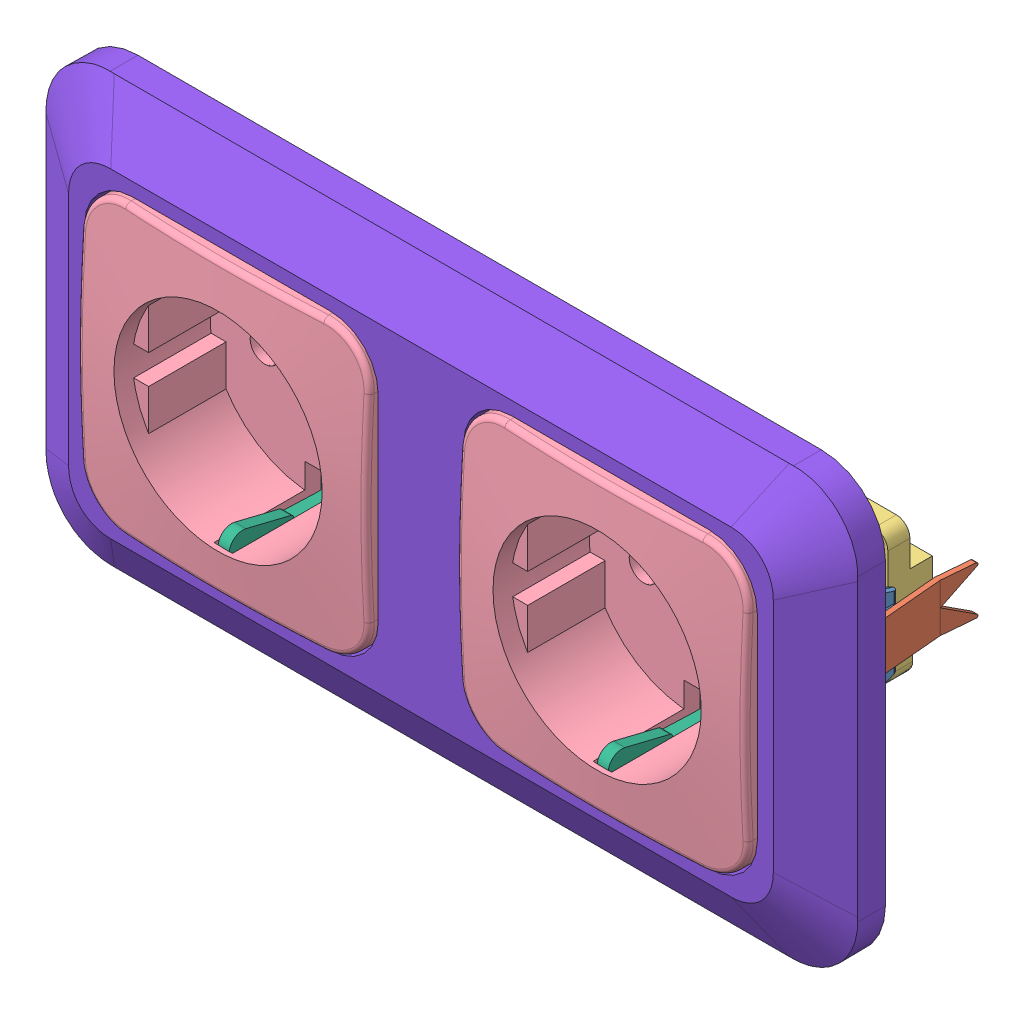
SolidWorks assembly Steckdose_2er, configuration Standard. Lengths in mm.
Overall size (152.53 80.54 45.48).
17 component instances, 8 part files, 0 mates.
Components (placement in the parent):
- Montageplatte.02-1: Montageplatte.02 [Standard] at (-71 0 0) size (71 71 18.97)
- Kralle.04-1: Kralle.04 [Standard] at (82.9962 101.8382 0) x (-1 0 0) z (0 0 1) size (8.78 9.01 23.36)
- Halter-1: Halter [Standard] at (-71 0 0) size (45.97 31.9 15.37)
- Buchse-1: Buchse [Standard] at (-71 0 0) size (64.03 64.03 27)
- Stromklemme_1.02-1: Stromklemme_1.02 [Standard] at (-71 0 0) size (8.38 19.82 12.51)
- Erdleiter-1: Erdleiter [Standard] at (-71 0 0) size (7.24 44.01 27.12)
- Kralle.04-2: Kralle.04 [Standard] at (-71 0 0) size (8.78 9.01 23.36)
- Stromklemme_2.02-1: Stromklemme_2.02 [Standard] at (-71 0 0) size (8.38 19.82 12.51)
- Montageplatte.02-2: Montageplatte.02 [Standard] at origin size (71 71 18.97)
- Kralle.04-3: Kralle.04 [Standard] at origin size (8.78 9.01 23.36)
- Erdleiter-2: Erdleiter [Standard] at origin size (7.24 44.01 27.12)
- Buchse-2: Buchse [Standard] at origin size (64.03 64.03 27)
- Halter-2: Halter [Standard] at origin size (45.97 31.9 15.37)
- Kralle.04-4: Kralle.04 [Standard] at (153.9962 101.8382 0) x (-1 0 0) z (0 0 1) size (8.78 9.01 23.36)
- Stromklemme_1.02-2: Stromklemme_1.02 [Standard] at origin size (8.38 19.82 12.51)
- Stromklemme_2.02-2: Stromklemme_2.02 [Standard] at origin size (8.38 19.82 12.51)
- Wandplatte_2er-1: Wandplatte_2er [Standard] at origin size (152.53 80.54 11)
